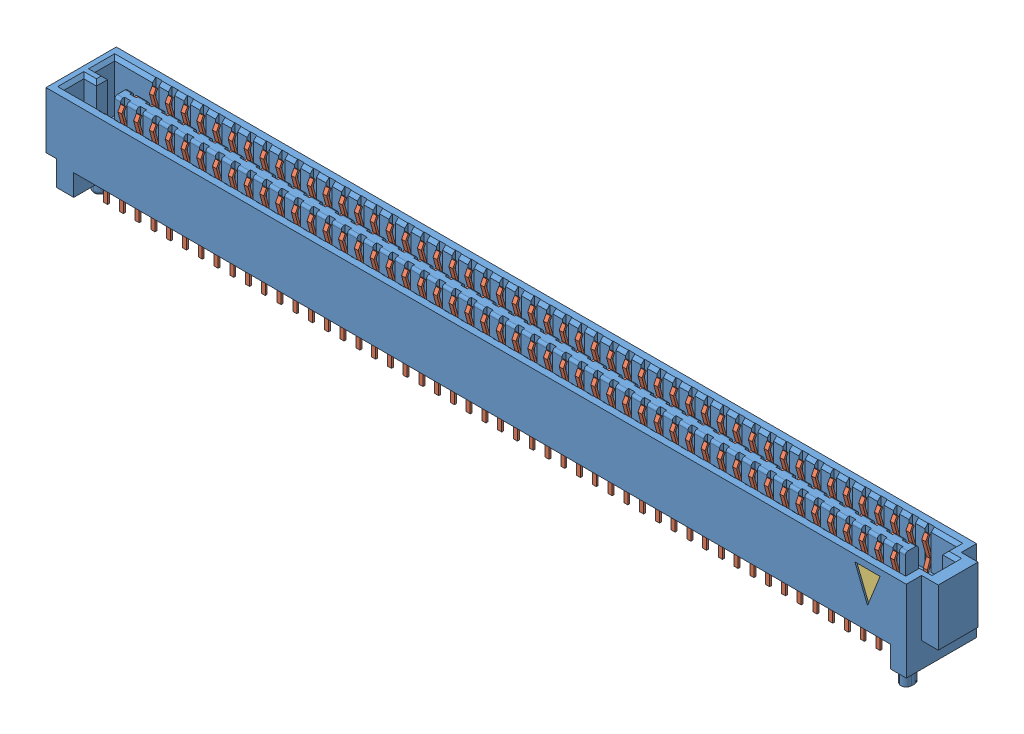
SolidWorks assembly Assem2, configuration Default. Lengths in mm.
Overall size (70.66 7.82 5.66).
5 component instances, 4 part files, 3 mates.
Components (placement in the parent):
- SEAF_50_06_5_L_04_2_A_K_TR-1: SEAF_50_06_5_L_04_2_A_K_TR [Default] at (0.254 1.7272 -0.0032) size (70.66 7.82 5.66)
  - _SEAF_50_06_5_L_04_1_A_0_K_TR_BODY_2_2-1: _SEAF_50_06_5_L_04_1_A_0_K_TR_BODY_2_2 [Default] at origin size (70.66 7.82 5.66)
  - _SEAF_50_06_5_L_04_1_A_0_K_TR_cCON2_4-1: _SEAF_50_06_5_L_04_1_A_0_K_TR_cCON2_4 [Default] at origin size (62.55 6.17 5.41)
  - _SEAF_04_K_PAD_6-1: _SEAF_04_K_PAD_6 [Default] at (-0.2286 4.826 0) size (6.5 0.13 6.5) (hidden)
  - _SEAF_TRIANGLE_FIRST_PIN_8-1: _SEAF_TRIANGLE_FIRST_PIN_8 [Default] at (30.861 1.27 2.5781) size (2.03 2.54 0.13)
Mates (geometry in assembly coordinates):
- Coincident1: coincident: plane of ? through (0.254 0 -0.0032) normal (0 -1 0)
- Coincident2: coincident: line of ? through (-2.9282 0 1.7272) axis (-0.000003 -1 0)
- Coincident3: coincident: unknown of ?
